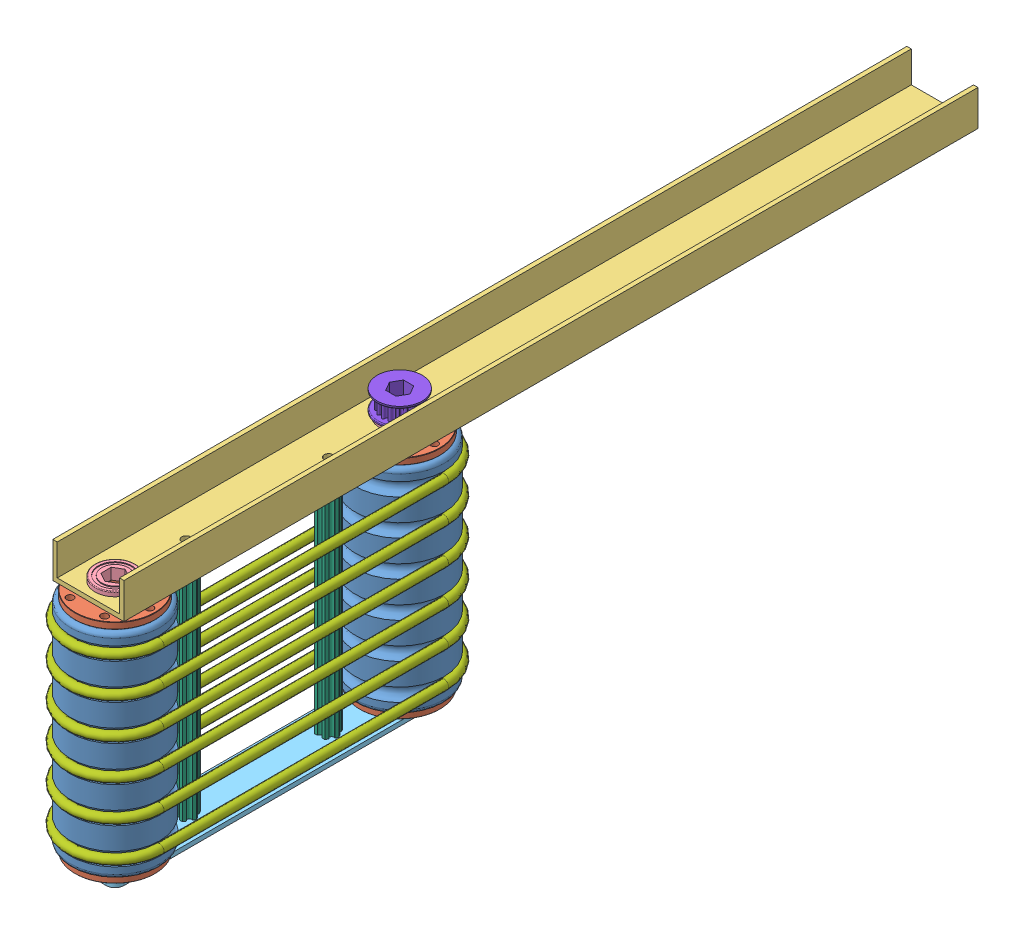
SolidWorks assembly Assem2, configuration Default. Lengths in mm.
Overall size (87.32 198.17 634.21).
21 component instances, 8 part files, 32 mates.
Components (placement in the parent):
- Roller-1: Roller [Default] at (106.9288 96.8013 440.1818) x (0.852613 0 0.522543) z (-0.522543 0 0.852613) size (63.5 152.4 63.5)
- am-0096a_Hex_Hub-1: am-0096a_Hex_Hub [Default] at (106.9288 235.2773 440.1818) x (0 -1 0) z (0.466376 0 -0.884587) size (25.4 57.15 57.15)
- am-0096a_Hex_Hub-2: am-0096a_Hex_Hub [Default] at (106.9288 110.7254 440.1818) x (0 1 0) z (-0.532886 0 -0.846187) size (25.4 57.15 57.15)
- Arm-1: Arm [Default] at (81.5288 256.1863 -150.3682) size (50.8 25.4 609.6)
- Hex_Bearing-1: Hex_Bearing [Default] at (106.9288 262.5897 440.1818) x (-0.838312 0 -0.545191) z (0 -1 0) size (31.12 31.12 7.93)
- Hex_Bearing-2: Hex_Bearing [Default] at (106.9288 262.5897 236.9818) x (-0.838312 0 -0.545191) z (0 -1 0) size (31.12 31.12 7.93)
- am-0096a_Hex_Hub-3: am-0096a_Hex_Hub [Default] at (106.9288 235.2773 236.9818) x (0 -1 0) z (0.466376 0 -0.884587) size (25.4 57.15 57.15)
- Roller-2: Roller [Default] at (106.9288 96.8013 236.9818) x (0.971171 0 -0.238383) z (0.238383 0 0.971171) size (63.5 152.4 63.5)
- am-0096a_Hex_Hub-4: am-0096a_Hex_Hub [Default] at (106.9288 110.7254 236.9818) x (0 1 0) z (-0.532886 0 -0.846187) size (25.4 57.15 57.15)
- Hex_Bearing-3: Hex_Bearing [Default] at (106.9288 83.413 440.1818) x (0.999998 0 0.002092) z (0 1 0) size (31.12 31.12 7.93)
- Hex_Bearing-4: Hex_Bearing [Default] at (106.9288 83.413 236.9818) x (-0.08884 0 -0.996046) z (0 1 0) size (31.12 31.12 7.93)
- Arm_Lowwer-1: Arm_Lowwer [Default] at (106.9288 86.6413 440.1818) x (0 0 -1) z (1 0 0) size (241.3 3.17 38.1)
- Claw_Churo-1: Claw_Churo [Default] at (106.9288 256.1863 389.3818) x (1 0 0) z (0 -1 0) size (14.66 12.7 166.37)
- Claw_Churo-2: Claw_Churo [Default] at (106.9288 256.1863 287.7818) x (1 0 0) z (0 -1 0) size (14.66 12.7 166.37)
- Polycord-1: Polycord [Default] at (106.9288 236.4297 440.1818) x (0 0 -1) z (1 0 0) size (273.05 6.35 69.85)
- Sproket_Small_-1: Sproket_Small_ [Default] at (106.9288 275.0992 236.9818) x (1 0 0) z (0 -1 0) size (32 32 14.1)
- Polycord-2: Polycord [Default] at (106.9288 211.0297 440.1818) x (0 0 -1) z (1 0 0) size (273.05 6.35 69.85)
- Polycord-3: Polycord [Default] at (106.9288 185.6297 440.1818) x (0 0 -1) z (1 0 0) size (273.05 6.35 69.85)
- Polycord-4: Polycord [Default] at (106.9288 160.2297 440.1818) x (0 0 -1) z (1 0 0) size (273.05 6.35 69.85)
- Polycord-5: Polycord [Default] at (106.9288 134.8297 440.1818) x (0 0 -1) z (1 0 0) size (273.05 6.35 69.85)
- Polycord-6: Polycord [Default] at (106.9288 109.4297 440.1818) x (0 0 -1) z (1 0 0) size (273.05 6.35 69.85)
Mates (geometry in assembly coordinates):
- Coincident1: coincident anti-aligned: plane of Roller-1 through (106.9288 249.2013 440.1818) normal (0 1 0); plane of am-0096a_Hex_Hub-1 through (109.5994 249.2013 435.1164) normal (0 -1 0)
- Concentric1: concentric aligned: circle of Roller-1; circle of am-0096a_Hex_Hub-1
- Coincident2: coincident anti-aligned: plane of Roller-1 through (106.9288 96.8013 440.1818) normal (0 -1 0); plane of am-0096a_Hex_Hub-2 through (103.8773 96.8013 435.3362) normal (0 1 0)
- Concentric2: concentric aligned: circle of Roller-1; circle of am-0096a_Hex_Hub-2
- Concentric15: concentric anti-aligned: circle of Roller-1; circle of Polycord-1
- Parallel1: parallel aligned: plane of am-0096a_Hex_Hub-1 through (100.4168 254.6623 436.7485) normal (0.532886 0 0.846187); plane of am-0096a_Hex_Hub-2 through (106.6461 91.3403 432.8256) normal (0.532886 0 0.846187)
- Coincident10: coincident anti-aligned: plane of am-0096a_Hex_Hub-1 through (106.9288 254.6623 440.1818) normal (0 1 0); plane of Hex_Bearing-1 through (93.9932 254.6623 431.7693) normal (0 -1 0)
- Concentric3: concentric anti-aligned: circle of am-0096a_Hex_Hub-1; circle of Hex_Bearing-1
- Coincident17: coincident anti-aligned: plane of am-0096a_Hex_Hub-2 through (106.9288 91.3403 440.1818) normal (0 -1 0); plane of Hex_Bearing-3 through (122.3592 91.3403 440.2141) normal (0 1 0)
- Concentric9: concentric aligned: circle of am-0096a_Hex_Hub-2; circle of Hex_Bearing-3
- Concentric4: concentric anti-aligned: circle of Arm-1; circle of Hex_Bearing-1
- Coincident11: coincident anti-aligned: plane of Arm-1 through (81.5288 256.1863 459.2318) normal (0 -1 0); plane of Hex_Bearing-1 through (95.2176 256.1863 432.5655) normal (0 1 0)
- Concentric5: concentric anti-aligned: circle of Arm-1; circle of Hex_Bearing-2
- Coincident13: coincident anti-aligned: plane of Arm-1 through (81.5288 256.1863 459.2318) normal (0 -1 0); plane of Hex_Bearing-2 through (95.2176 256.1863 229.3655) normal (0 1 0)
- Coincident14: coincident anti-aligned: plane of Hex_Bearing-2 through (93.9932 254.6623 228.5693) normal (0 -1 0); plane of am-0096a_Hex_Hub-3 through (106.9288 254.6623 236.9818) normal (0 1 0)
- Concentric6: concentric anti-aligned: circle of Hex_Bearing-2; circle of am-0096a_Hex_Hub-3
- Coincident22: coincident anti-aligned: plane of Hex_Bearing-2 through (106.9288 262.5897 236.9818) normal (0 1 0); plane of Sproket_Small_-1 through (106.9288 262.5897 236.9818) normal (0 -1 0)
- Concentric17: concentric aligned: circle of Hex_Bearing-2; circle of Sproket_Small_-1
- Concentric7: concentric aligned: circle of am-0096a_Hex_Hub-3; circle of Roller-2
- Coincident15: coincident anti-aligned: plane of am-0096a_Hex_Hub-3 through (109.5994 249.2013 231.9164) normal (0 -1 0); plane of Roller-2 through (106.9288 249.2013 236.9818) normal (0 1 0)
- Concentric8: concentric aligned: circle of Roller-2; circle of am-0096a_Hex_Hub-4
- Coincident16: coincident anti-aligned: plane of Roller-2 through (106.9288 96.8013 236.9818) normal (0 -1 0); plane of am-0096a_Hex_Hub-4 through (103.8773 96.8013 232.1362) normal (0 1 0)
- Concentric16: concentric anti-aligned: circle of Roller-2; circle of Polycord-1
- Concentric10: concentric anti-aligned: circle of am-0096a_Hex_Hub-4; circle of Hex_Bearing-4
- Coincident18: coincident anti-aligned: plane of am-0096a_Hex_Hub-4 through (106.9288 91.3403 236.9818) normal (0 -1 0); plane of Hex_Bearing-4 through (105.5579 91.3403 221.6123) normal (0 1 0)
- Concentric11: concentric aligned: circle of Hex_Bearing-3; circle of Arm_Lowwer-1
- Coincident19: coincident anti-aligned: plane of Hex_Bearing-3 through (120.8987 89.8163 440.2111) normal (0 -1 0); plane of Arm_Lowwer-1 through (119.6288 89.8163 224.2818) normal (0 1 0)
- Concentric12: concentric aligned: circle of Hex_Bearing-4; circle of Arm_Lowwer-1
- Coincident20: coincident anti-aligned: plane of Arm_Lowwer-1 through (119.6288 89.8163 224.2818) normal (0 1 0); plane of Claw_Churo-1 through (112.428 89.8163 386.2068) normal (0 -1 0)
- Concentric13: concentric aligned: circle of Arm_Lowwer-1; circle of Claw_Churo-1
- Coincident21: coincident anti-aligned: plane of Arm_Lowwer-1 through (119.6288 89.8163 224.2818) normal (0 1 0); plane of Claw_Churo-2 through (112.428 89.8163 284.6068) normal (0 -1 0)
- Concentric14: concentric aligned: circle of Arm_Lowwer-1; circle of Claw_Churo-2
